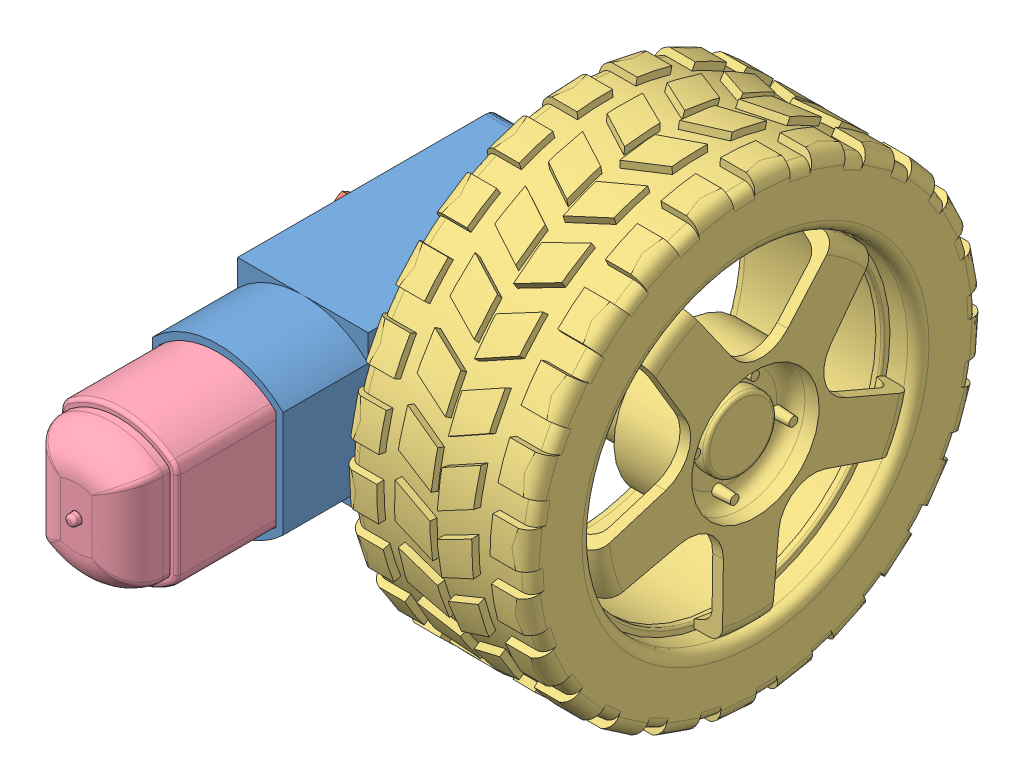
SolidWorks assembly Real Bo Motor With Wheel, configuration Default. Lengths in mm.
Overall size (57.67 89.91 102.96).
4 component instances, 4 part files, 11 mates.
Components (placement in the parent):
- Real Bo Motor Gear Box-1: Real Bo Motor Gear Box [Default] x (0 0 -1) z (1 0 0) size (54 22.5 18.44)
- Shaft-1: Shaft [Default] at (0 0 -7.5) x (0 0.501874 0.864941) z (1 0 0) size (7.2 7.2 37.26)
- Real Wheel-1: Real Wheel [Default] at (16.952 33.1259 -49.1831) x (1 0 0) z (0 -0.544629 0.838677) size (28.31 65 65)
- Real Bo Motor Frame-2: Real Bo Motor Frame [Default] at (0 0 18.5) x (-1 0 0) z (0 1 0) size (16.44 32 20.5)
Mates (geometry in assembly coordinates):
- Perpendicular1: perpendicular: plane of Real Bo Motor Gear Box-1 through (0 0 0) normal (1 0 0); plane of assembly through (0 0 0) normal (0 0 1)
- Coincident2: coincident anti-aligned: plane of Real Bo Motor Gear Box-1 through (0 0 0) normal (0 0 -1); plane of assembly through (0 0 0) normal (0 0 1)
- Coincident3: coincident aligned: plane of Real Bo Motor Gear Box-1 through (0 0 0) normal (0 1 0); plane of assembly through (0 0 0) normal (0 1 0)
- Coincident4: coincident aligned: plane of Real Bo Motor Gear Box-1 through (0 0 0) normal (1 0 0); plane of assembly through (0 0 0) normal (1 0 0)
- Concentric2: concentric anti-aligned: cylinder of Real Bo Motor Gear Box-1 through (-9.22 0 -7.5) axis (1 0 0) radius 2.75; cylinder of Shaft-1 through (9.23 0 -7.5) axis (-1 0 0) radius 2.7
- Width1: width anti-aligned: plane of Real Bo Motor Gear Box-1 through (-9.22 9.25 -17.5) normal (-1 0 0); plane of Shaft-1 through (9.22 9.25 -17.5) normal (1 0 0); plane of Real Bo Motor Gear Box-1 through (18.63 0 -7.5) normal (1 0 0); plane of Shaft-1 through (-18.63 0 -7.5) normal (-1 0 0)
- Coincident10: coincident anti-aligned: plane of Shaft-1 through (10.73 0 -7.5) normal (1 0 0); plane of Real Wheel-1 through (10.73 0 -7.5) normal (-1 0 0)
- Concentric8: concentric aligned: cylinder of Shaft-1 through (-10.73 0 -7.5) axis (1 0 0) radius 2.7; cylinder of Real Wheel-1 through (9.93 0 -7.5) axis (1 0 0) radius 3.6
- Coincident13: coincident anti-aligned: plane of Real Bo Motor Gear Box-1 through (0 -1.9595 18.5) normal (0 0 1); plane of Real Bo Motor Frame-2 through (0 -1.9595 18.5) normal (0 0 -1)
- Concentric11: concentric aligned: cylinder of Real Bo Motor Gear Box-1 through (0 -1.9595 29.5) axis (0 0 -1) radius 12.2095; cylinder of Real Bo Motor Frame-2 through (0 -1.9595 43.5) axis (0 0 -1) radius 12.2095
- Coincident14: coincident anti-aligned: plane of Real Bo Motor Gear Box-1 through (-8.22 9.25 -17.5) normal (1 0 0); plane of Real Bo Motor Frame-2 through (-8.22 7.0684 43.5) normal (-1 0 0)
